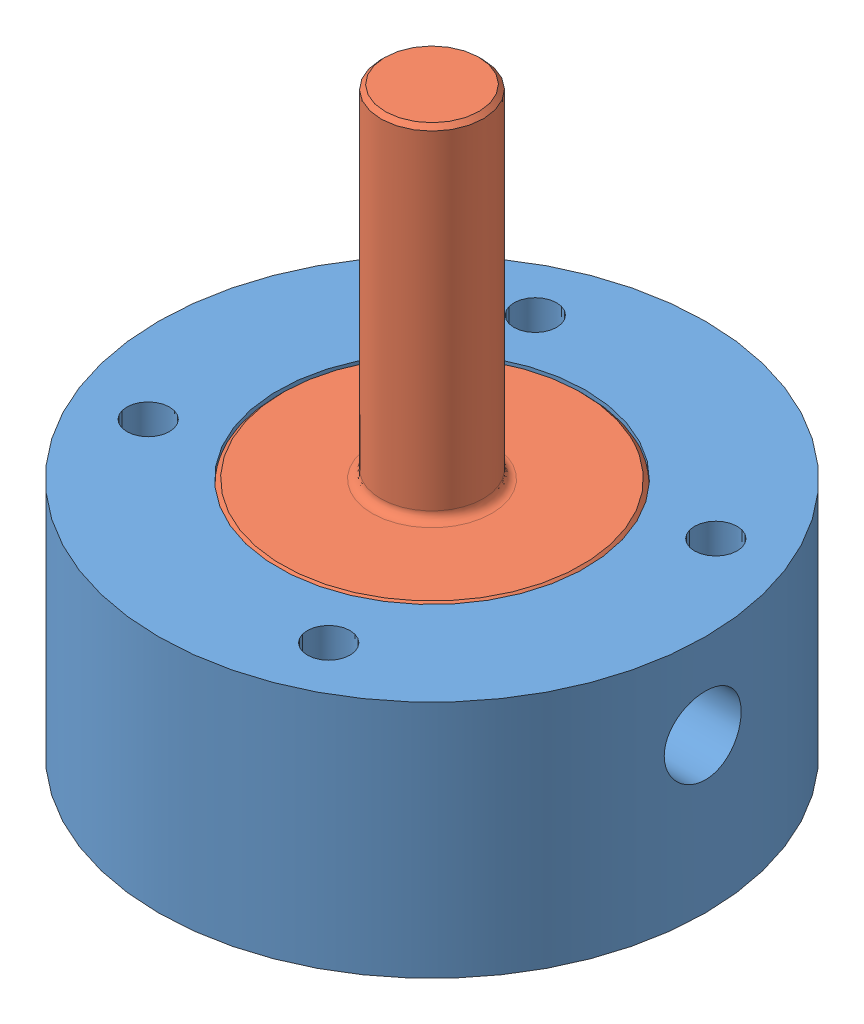
SolidWorks assembly Montagem_Shutter_v10, configuration Default. Lengths in mm.
Overall size (77.19 34.5 39.94).
2 component instances, 2 part files, 3 mates.
Components (placement in the parent):
- Sede_Inferior_v10-1: Sede_Inferior_v10 [Valor predeterminado<Como usinado>] at origin size (77.19 14 39.94)
- Desviador_v10-1: Desviador_v10 [Valor predeterminado] x (-0.872843 0 -0.488) z (0.488 0 -0.872843) size (18 34.5 18)
Mates (geometry in assembly coordinates):
- Coincident1: coordinate: point of Sede_Inferior_v10-1; point of assembly
- Concentric1: concentric aligned: cylinder of Sede_Inferior_v10-1 through (0 -9 0) axis (0 -1 0) radius 3; cylinder of Desviador_v10-1 through (0 0 0) axis (0 -1 0) radius 3
- Coincident2: coincident anti-aligned: plane of Sede_Inferior_v10-1 through (9 -5 0) normal (0 1 0); plane of Desviador_v10-1 through (-2.6185 -5 -1.464) normal (0 -1 0)
